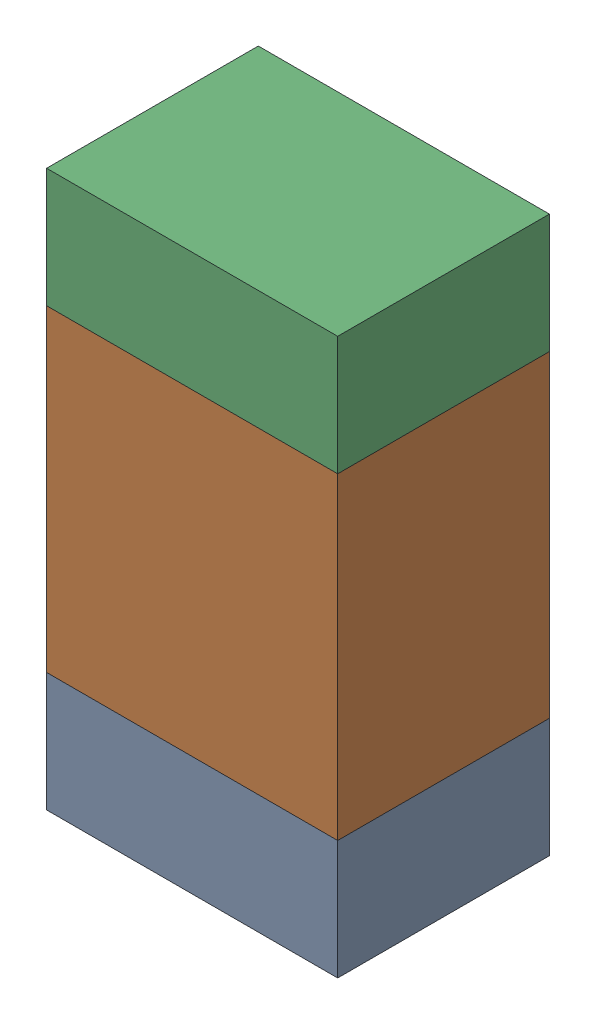
SolidWorks assembly R101_1PCB, configuration Default. Lengths in mm.
Overall size (0.55 1.05 0.4).
6 component instances, 2 part files, 0 mates.
Components (placement in the parent):
- 846483288-1: 846483288 [Default] at (117.0999 118.4876 0) size (0.55 0.22 0.4)
  - Extruded_12-1: Extruded_12 [Default] at origin size (0.55 0.22 0.4)
- 846483424-1: 846483424 [Default] at (117.0999 118.9001 0) size (0.55 0.6 0.4)
  - Extruded_13-1: Extruded_13 [Default] at origin size (0.55 0.6 0.4)
- 846483288-2: 846483288 [Default] at (117.0999 119.3126 0) size (0.55 0.22 0.4)
  - Extruded_12-1: Extruded_12 [Default] at origin size (0.55 0.22 0.4)
